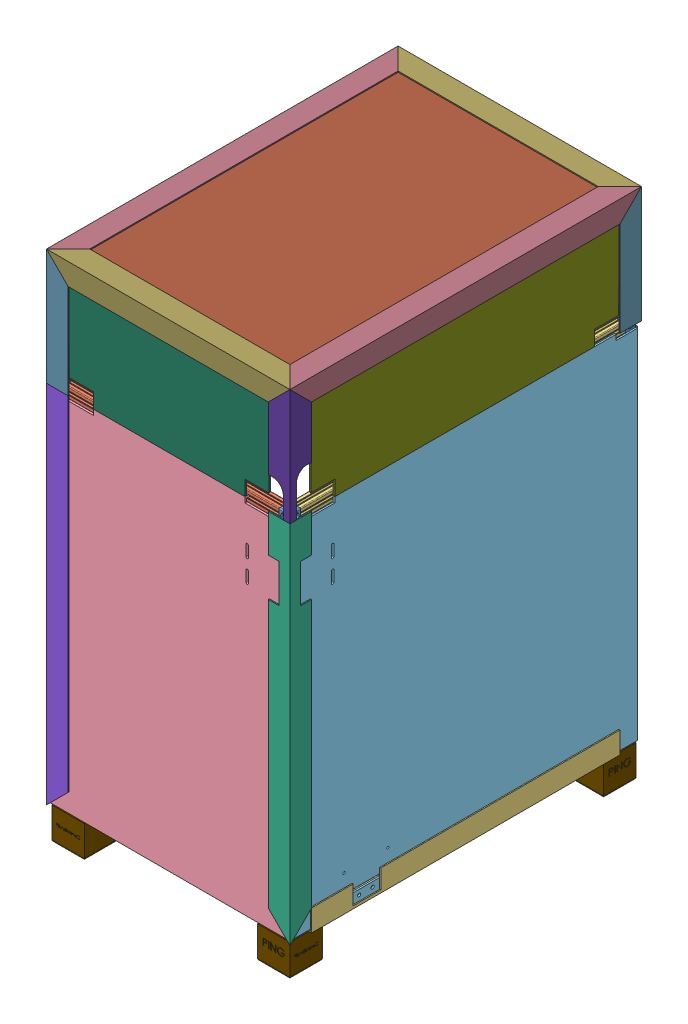
SolidWorks assembly carcasse, configuration Défaut. Lengths in mm.
Overall size (450 950 650).
53 component instances, 24 part files, 63 mates.
Components (placement in the parent):
- cadre-1: cadre [Défaut] at (-215.194 -19.8636 -400) size (440 20 640)
  - Blocks-1: Blocks [Défaut] at (-153.6103 82.5412 1245.1575) x (0 1 0) z (0 0 1) size (20 20 20)
  - Blocks-3: Blocks [Défaut] at (-153.6103 62.5412 625.1575) x (0 0 -1) z (0 1 0) size (20 20 20)
  - Blocks-4: Blocks [Défaut] at (246.3897 82.5412 645.1575) x (0 1 0) z (0 0 -1) size (20 20 20)
  - Blocks-5: Blocks [Défaut] at (246.3897 62.5412 1265.1575) x (0 0 1) z (0 1 0) size (20 20 20)
  - prof_20x20x400mm-1: prof_20x20x400mm [End Finishing_Non-Machined End Finish Options_Type_Single_] at (246.3897 72.5412 635.1575) x (0 0 1) z (-1 0 0) size (20 20 400)
  - prof_20x20x400mm-2: prof_20x20x400mm [End Finishing_Non-Machined End Finish Options_Type_Single_] at (246.3897 72.5412 1255.1575) x (0 0 1) z (-1 0 0) size (20 20 400)
  - prof_20x20x600mm-4: prof_20x20x600mm [End Finishing_Non-Machined End Finish Options_Type_Single_] at (256.3897 72.5412 645.1575) size (20 20 600)
  - prof_20x20x600mm-5: prof_20x20x600mm [End Finishing_Non-Machined End Finish Options_Type_Single_] at (-163.6103 72.5412 645.1575) size (20 20 600)
- prof_20x20x640mm-1: prof_20x20x640mm [End Finishing_Non-Machined End Finish Options_Type_Single_] at (41.1957 42.6776 235.1575) x (1 0 0) z (0 -1 0) size (20 20 640)
- prof_20x20x640mm-2: prof_20x20x640mm [End Finishing_Non-Machined End Finish Options_Type_Single_] at (41.1957 42.6776 855.1575) x (1 0 0) z (0 -1 0) size (20 20 640)
- prof_20x20x640mm-3: prof_20x20x640mm [End Finishing_Non-Machined End Finish Options_Type_Single_] at (-378.8043 42.6776 855.1575) x (1 0 0) z (0 -1 0) size (20 20 640)
- prof_20x20x640mm-4: prof_20x20x640mm [End Finishing_Non-Machined End Finish Options_Type_Single_] at (-378.8043 42.6776 235.1575) x (1 0 0) z (0 -1 0) size (20 20 640)
- cadre-2: cadre [Défaut] at (-122.4146 -534.7812 -400) x (-1 0 0) z (0 0 1) size (440 20 640)
  - Blocks-1: Blocks [Défaut] at (-153.6103 82.5412 1245.1575) x (0 1 0) z (0 0 1) size (20 20 20)
  - Blocks-3: Blocks [Défaut] at (-153.6103 62.5412 625.1575) x (0 0 -1) z (0 1 0) size (20 20 20)
  - Blocks-4: Blocks [Défaut] at (246.3897 82.5412 645.1575) x (0 1 0) z (0 0 -1) size (20 20 20)
  - Blocks-5: Blocks [Défaut] at (246.3897 62.5412 1265.1575) x (0 0 1) z (0 1 0) size (20 20 20)
  - prof_20x20x400mm-1: prof_20x20x400mm [End Finishing_Non-Machined End Finish Options_Type_Single_] at (246.3897 72.5412 635.1575) x (0 0 1) z (-1 0 0) size (20 20 400)
  - prof_20x20x400mm-2: prof_20x20x400mm [End Finishing_Non-Machined End Finish Options_Type_Single_] at (246.3897 72.5412 1255.1575) x (0 0 1) z (-1 0 0) size (20 20 400)
  - prof_20x20x600mm-4: prof_20x20x600mm [End Finishing_Non-Machined End Finish Options_Type_Single_] at (256.3897 72.5412 645.1575) size (20 20 600)
  - prof_20x20x600mm-5: prof_20x20x600mm [End Finishing_Non-Machined End Finish Options_Type_Single_] at (-163.6103 72.5412 645.1575) size (20 20 600)
- plaque_acrylique_680x670-2: plaque_acrylique_680x670 [Défaut] at (51.1957 -282.3224 525.1575) x (0 0 -1) z (1 0 0) size (640 670 3)
- plaque_acrylique_380x670_G-1: plaque_acrylique_380x670_G [Défaut] at (-138.8043 -282.3224 222.1575) size (440 670 3)
- plaque_acrylique_680x670_porte-1: plaque_acrylique_680x670_porte [Défaut] at (-391.8043 -282.3224 525.1575) x (0 0 -1) z (1 0 0) size (640 670 3)
- eclisse_40x40x670_bisote_x1-1: eclisse_40x40x670_bisote_x1 [Défaut] at (-373.8043 -622.3224 240.2711) size (40 675 40)
- eclisse_40x40x670_bisote_x1-2: eclisse_40x40x670_bisote_x1 [Défaut] at (-373.6907 -622.3224 850.1575) x (0 0 -1) z (1 0 0) size (40 675 40)
- eclisse_40x40x670_bisote_x1-4: eclisse_40x40x670_bisote_x1 [Défaut] at (36.0821 -622.3224 240.1575) x (0 0 1) z (-1 0 0) size (40 675 40) (hidden)
- couvercle-1: couvercle [Défaut] at (191.3923 156.5575 835.9918) size (450 215 650)
  - plaque_acrylique_680x210-2: plaque_acrylique_680x210 [Défaut] at (-583.1966 1.1201 -270.8343) x (0 0 -1) z (1 0 0) size (640 210 3)
  - plaque_acrylique_380x210-2: plaque_acrylique_380x210 [Défaut] at (-330.1966 1.1201 -613.8343) size (440 210 3)
  - plaque_acrylique_380x680-1: plaque_acrylique_380x680 [Défaut] at (-330.1966 106.1201 -270.8343) x (1 0 0) z (0 1 0) size (440 640 3)
  - eclisse_40x40x404_bisote_x2-1: eclisse_40x40x404_bisote_x2 [Défaut] at (-135.1966 91.0065 -595.8343) x (0 0 1) z (0 -1 0) size (40 450 40)
  - eclisse_40x40x704_bisote_x2-1: eclisse_40x40x704_bisote_x2 [Défaut] at (-155.3102 91.1201 -615.8343) x (0 -1 0) z (-1 0 0) size (40 650 40)
  - eclisse_40x40x404_bisote_x2-2: eclisse_40x40x404_bisote_x2 [Défaut] at (-585.1966 91.0065 14.1657) x (0 0 -1) z (0 -1 0) size (40 450 40)
  - eclisse_40x40x704_bisote_x2-2: eclisse_40x40x704_bisote_x2 [Défaut] at (-565.1966 91.0065 -615.8343) x (1 0 0) z (0 -1 0) size (40 650 40)
  - eclisse_40x40x222_bisote_x1-1: eclisse_40x40x222_bisote_x1 [Défaut] at (-565.083 111.1201 -595.8343) x (0 0 1) z (1 0 0) size (40 215 40)
  - eclisse_40x40x222_bisote_x1-2: eclisse_40x40x222_bisote_x1 [Défaut] at (-155.1966 111.1201 -595.7207) x (-1 0 0) z (0 0 1) size (40 215 40)
  - eclisse_40x40x222_bisote_x1-4: eclisse_40x40x222_bisote_x1 [Défaut] at (-565.1966 111.1201 14.052) x (1 0 0) z (0 0 -1) size (40 215 40)
  - plaque_acrylique_380x210_Moteur-1: plaque_acrylique_380x210_Moteur [Défaut] at (-330.1966 1.1201 29.1657) size (440 210 3)
  - plaque_acrylique_680x210_moteur-1: plaque_acrylique_680x210_moteur [Défaut] at (-140.1966 1.1201 -270.8343) x (0 0 -1) z (1 0 0) size (640 210 3)
  - eclisse_40x40x222_bisote_x1_Moteur-1: eclisse_40x40x222_bisote_x1_Moteur [Défaut] at (-155.3102 111.1201 14.1657) x (0 0 -1) z (-1 0 0) size (40 215 40)
- Pied-1: Pied [Défaut] at (-8.8043 -622.3224 285.1575) x (-1 0 0) z (0 -1 0) size (60 60 60)
- Pied-2: Pied [Défaut] at (-8.8043 -622.3224 805.1575) x (0 0 -1) z (0 -1 0) size (60 60 60)
- Pied-3: Pied [Défaut] at (-328.8043 -622.3224 805.1575) x (1 0 0) z (0 -1 0) size (60 60 60)
- Pied-4: Pied [Défaut] at (-328.8043 -622.3224 285.1575) x (0 0 1) z (0 -1 0) size (60 60 60)
- eclisse_bas_40x40x704-2: eclisse_bas_40x40x704 [Défaut] at (-373.8043 -602.2087 830.1575) x (1 0 0) z (0 1 0) size (40 570 40) (hidden)
- eclisse_bas_40x40x404-1: eclisse_bas_40x40x404 [Défaut] at (-353.8043 -602.2087 240.1575) x (0 0 1) z (0 1 0) size (40 370 40) (hidden)
- eclisse_bas_40x40x404-2: eclisse_bas_40x40x404 [Défaut] at (16.1957 -602.2087 850.1575) x (0 0 -1) z (0 1 0) size (40 370 40) (hidden)
- eclisse_bas_support_Z_40x40x704-1: eclisse_bas_support_Z_40x40x704 [Défaut] at (36.0821 -602.3224 830.1575) x (0 1 0) z (-1 0 0) size (40 570 40) (hidden)
- plaque_acrylique_380x670_D-2: plaque_acrylique_380x670_D [Défaut] at (-198.8043 -282.3224 848.1575) x (-1 0 0) z (0 0 -1) size (440 670 23) (hidden)
- plaque_acrylique_bas_380x680-1: plaque_acrylique_bas_380x680 [Défaut] at (-138.8043 -620.3224 565.1575) x (1 0 0) z (0 1 0) size (440 640 3)
- eclisse_40x40x670_bisote_x1-Moteur-1: eclisse_40x40x670_bisote_x1-Moteur [Défaut] at (36.1957 -622.3224 850.0438) x (-1 0 0) z (0 0 -1) size (40 675 40) (hidden)
Mates (geometry in assembly coordinates):
- Coïncidente66: coincident anti-aligned: plane of plaque_acrylique_680x670_porte-1 through (-391.8043 -282.3224 525.1575) normal (-1 0 0); plane of eclisse_40x40x670_bisote_x1-1 through (-391.8043 52.6776 222.1575) normal (1 0 0)
- Coïncidente67: coincident aligned: plane of plaque_acrylique_680x670_porte-1 through (-388.8043 52.6776 865.1575) normal (0 1 0); plane of eclisse_40x40x670_bisote_x1-1 through (-373.8043 52.6776 240.2711) normal (0 1 0)
- Coïncidente68: coincident anti-aligned: plane of plaque_acrylique_680x670-2 through (54.1957 -282.3224 525.1575) normal (1 0 0); plane of eclisse_40x40x670_bisote_x1-4 through (54.1957 52.6776 222.1575) normal (-1 0 0)
- Coïncidente72: coincident anti-aligned: plane of plaque_acrylique_680x670_porte-1 through (-391.8043 -282.3224 525.1575) normal (-1 0 0); plane of eclisse_40x40x670_bisote_x1-2 through (-391.8043 52.6776 868.1575) normal (1 0 0)
- Coïncidente100: coincident: plane of plaque_acrylique_680x670_porte-1 through (-388.8043 52.6776 865.1575) normal (0 1 0); line of eclisse_40x40x670_bisote_x1-2 through (-391.8043 52.6776 868.1575) axis (0 0 -1)
- Coïncidente132: coincident anti-aligned: plane of plaque_acrylique_680x670_porte-1 through (-391.8043 -282.3224 525.1575) normal (-1 0 0); plane of eclisse_bas_40x40x704-2 through (-391.8043 -620.3224 260.1575) normal (1 0 0)
- Coïncidente134: coincident anti-aligned: line of eclisse_40x40x670_bisote_x1-2 through (-393.8043 52.6776 830.1575) axis (0 -1 0); line of eclisse_bas_40x40x704-2 through (-393.8043 -622.3224 830.1575) axis (0 1 0)
- Coïncidente142: coincident anti-aligned: plane of plaque_acrylique_680x670-2 through (54.1957 -282.3224 525.1575) normal (1 0 0); plane of eclisse_bas_support_Z_40x40x704-1 through (54.1957 -620.3224 260.1575) normal (-1 0 0)
- Coïncidente156: coincident anti-aligned: plane of eclisse_bas_40x40x404-2 through (-353.8043 -620.3224 868.1575) normal (0 0 -1); plane of plaque_acrylique_380x670_D-2 through (-198.8043 -282.3224 868.1575) normal (0 0 1)
- Coïncidente157: coincident anti-aligned: plane of eclisse_40x40x670_bisote_x1-2 through (-391.8043 52.6776 868.1575) normal (0 0 -1); plane of plaque_acrylique_380x670_D-2 through (-198.8043 -282.3224 868.1575) normal (0 0 1)
- Coïncidente163: coincident anti-aligned: plane of cadre-1/Blocks-1 through (-388.8043 42.6776 865.1575) normal (0 -1 0); plane of prof_20x20x640mm-3 through (-387.3043 42.6776 863.6575) normal (0 1 0)
- Coïncidente164: coincident aligned: plane of cadre-1/Blocks-1 through (-388.8043 42.6776 865.1575) normal (-1 0 0); plane of prof_20x20x640mm-3 through (-388.8043 -597.3224 858.9075) normal (-1 0 0)
- Coïncidente165: coincident aligned: plane of cadre-1/Blocks-1 through (-368.8043 62.6776 865.1575) normal (0 0 1); plane of prof_20x20x640mm-3 through (-382.5543 -597.3224 865.1575) normal (0 0 1)
- Coïncidente166: coincident anti-aligned: plane of prof_20x20x640mm-3 through (-387.3043 -597.3224 863.6575) normal (0 -1 0); plane of cadre-2/Blocks-5 through (-368.8043 -597.3224 865.1575) normal (0 1 0)
- Coïncidente167: coincident aligned: plane of prof_20x20x640mm-3 through (-382.5543 -597.3224 865.1575) normal (0 0 1); plane of cadre-2/Blocks-5 through (-388.8043 -617.3224 865.1575) normal (0 0 1)
- Coïncidente168: coincident aligned: plane of prof_20x20x640mm-3 through (-388.8043 -597.3224 858.9075) normal (-1 0 0); plane of cadre-2/Blocks-5 through (-388.8043 -617.3224 845.1575) normal (-1 0 0)
- Coïncidente169: coincident anti-aligned: plane of prof_20x20x640mm-2 through (32.6957 -597.3224 863.6575) normal (0 -1 0); plane of cadre-2/Blocks-1 through (51.1957 -597.3224 865.1575) normal (0 1 0)
- Coïncidente170: coincident aligned: plane of prof_20x20x640mm-2 through (37.4457 -597.3224 865.1575) normal (0 0 1); plane of cadre-2/Blocks-1 through (31.1957 -617.3224 865.1575) normal (0 0 1)
- Coïncidente171: coincident aligned: plane of prof_20x20x640mm-2 through (51.1957 -597.3224 858.9075) normal (1 0 0); plane of cadre-2/Blocks-1 through (51.1957 -597.3224 865.1575) normal (1 0 0)
- Coïncidente172: coincident anti-aligned: plane of prof_20x20x640mm-1 through (32.6957 -597.3224 243.6575) normal (0 -1 0); plane of cadre-2/Blocks-3 through (31.1957 -597.3224 225.1575) normal (0 1 0)
- Coïncidente173: coincident aligned: plane of prof_20x20x640mm-1 through (51.1957 -597.3224 238.9075) normal (1 0 0); plane of cadre-2/Blocks-3 through (51.1957 -617.3224 245.1575) normal (1 0 0)
- Coïncidente174: coincident aligned: plane of prof_20x20x640mm-1 through (44.9457 -597.3224 225.1575) normal (0 0 -1); plane of cadre-2/Blocks-3 through (51.1957 -617.3224 225.1575) normal (0 0 -1)
- Coïncidente175: coincident aligned: plane of cadre-1/Blocks-3 through (-388.8043 62.6776 245.1575) normal (-1 0 0); plane of prof_20x20x640mm-4 through (-388.8043 -597.3224 231.4075) normal (-1 0 0)
- Coïncidente176: coincident aligned: plane of cadre-1/Blocks-3 through (-388.8043 62.6776 225.1575) normal (0 0 -1); plane of prof_20x20x640mm-4 through (-382.5543 -597.3224 225.1575) normal (0 0 -1)
- Coïncidente177: coincident anti-aligned: plane of cadre-1/Blocks-3 through (-368.8043 42.6776 225.1575) normal (0 -1 0); plane of prof_20x20x640mm-4 through (-387.3043 42.6776 243.6575) normal (0 1 0)
- Coïncidente183: coincident aligned: plane of prof_20x20x640mm-2 through (51.1957 -597.3224 858.9075) normal (1 0 0); plane of plaque_acrylique_380x670_D-2 through (51.1957 52.6776 868.1575) normal (1 0 0)
- Coïncidente186: coincident aligned: plane of cadre-1/prof_20x20x400mm-2 through (-368.8043 56.4276 865.1575) normal (0 0 1); plane of plaque_acrylique_680x670-2 through (54.1957 52.6776 865.1575) normal (0 0 1)
- Coïncidente187: coincident aligned: plane of cadre-1/prof_20x20x400mm-1 through (-368.8043 48.9276 225.1575) normal (0 0 -1); plane of plaque_acrylique_680x670_porte-1 through (-388.8043 52.6776 225.1575) normal (0 0 -1)
- Coïncidente191: coincident anti-aligned: plane of cadre-2/prof_20x20x400mm-1 through (31.1957 -617.3224 238.9075) normal (0 -1 0); plane of plaque_acrylique_bas_380x680-1 through (-138.8043 -617.3224 565.1575) normal (0 1 0)
- Coïncidente192: coincident aligned: plane of cadre-2/prof_20x20x400mm-2 through (31.1957 -611.0724 865.1575) normal (0 0 1); plane of plaque_acrylique_bas_380x680-1 through (-388.8043 -617.3224 865.1575) normal (0 0 1)
- Coïncidente204: coincident anti-aligned: plane of prof_20x20x640mm-1 through (44.9457 -597.3224 225.1575) normal (0 0 -1); plane of plaque_acrylique_380x670_G-1 through (-138.8043 -282.3224 225.1575) normal (0 0 1)
- Coïncidente205: coincident aligned: plane of cadre-2/prof_20x20x400mm-1 through (31.1957 -617.3224 231.4075) normal (0 -1 0); plane of plaque_acrylique_380x670_G-1 through (-388.8043 -617.3224 225.1575) normal (0 -1 0)
- Coïncidente206: coincident aligned: plane of prof_20x20x640mm-1 through (51.1957 -597.3224 231.4075) normal (1 0 0); plane of plaque_acrylique_380x670_G-1 through (51.1957 52.6776 225.1575) normal (1 0 0)
- Coïncidente207: coincident anti-aligned: plane of prof_20x20x640mm-4 through (-388.8043 -597.3224 231.4075) normal (-1 0 0); plane of plaque_acrylique_680x670_porte-1 through (-388.8043 -282.3224 525.1575) normal (1 0 0)
- Coïncidente208: coincident anti-aligned: plane of plaque_acrylique_380x670_G-1 through (-138.8043 -282.3224 222.1575) normal (0 0 -1); plane of eclisse_40x40x670_bisote_x1-1 through (-391.8043 52.6776 222.1575) normal (0 0 1)
- Coïncidente210: coincident anti-aligned: plane of plaque_acrylique_380x670_G-1 through (-138.8043 -282.3224 222.1575) normal (0 0 -1); plane of eclisse_40x40x670_bisote_x1-4 through (54.1957 52.6776 222.1575) normal (0 0 1)
- Coïncidente218: coincident: plane of cadre-2/prof_20x20x400mm-2 through (31.1957 -617.3224 858.9075) normal (0 -1 0); line of plaque_acrylique_380x670_D-2 through (51.1957 -617.3224 868.1575) axis (-1 0 0)
- Coïncidente223: coincident anti-aligned: plane of eclisse_bas_support_Z_40x40x704-1 through (54.1957 -620.3224 260.1575) normal (0 1 0); plane of plaque_acrylique_bas_380x680-1 through (-138.8043 -620.3224 565.1575) normal (0 -1 0)
- Coïncidente224: coincident anti-aligned: plane of eclisse_bas_40x40x704-2 through (-391.8043 -620.3224 260.1575) normal (0 1 0); plane of plaque_acrylique_bas_380x680-1 through (-138.8043 -620.3224 565.1575) normal (0 -1 0)
- Coïncidente225: coincident anti-aligned: plane of plaque_acrylique_380x670_G-1 through (-138.8043 -282.3224 222.1575) normal (0 0 -1); plane of eclisse_bas_40x40x404-1 through (16.1957 -620.3224 222.1575) normal (0 0 1)
- Coïncidente226: coincident anti-aligned: plane of eclisse_bas_40x40x404-1 through (16.1957 -620.3224 222.1575) normal (0 1 0); plane of plaque_acrylique_bas_380x680-1 through (-138.8043 -620.3224 565.1575) normal (0 -1 0)
- Coïncidente232: coincident aligned: plane of plaque_acrylique_380x670_G-1 through (-138.8043 -282.3224 222.1575) normal (0 0 -1); plane of couvercle-1/plaque_acrylique_380x210-2 through (-138.8043 157.6776 222.1575) normal (0 0 -1)
- Coïncidente233: coincident aligned: plane of couvercle-1/plaque_acrylique_380x210_Moteur-1 through (-138.8043 157.6776 868.1575) normal (0 0 1); plane of plaque_acrylique_380x670_D-2 through (-198.8043 -282.3224 868.1575) normal (0 0 1)
- Coïncidente234: coincident anti-aligned: line of plaque_acrylique_680x670-2 through (54.1957 52.6776 265.1575) axis (0 0 1); line of couvercle-1/plaque_acrylique_680x210_moteur-1 through (54.1957 52.6776 785.1575) axis (0 0 -1)
- Coïncidente235: coincident aligned: plane of plaque_acrylique_680x670-2 through (54.1957 -282.3224 525.1575) normal (1 0 0); plane of couvercle-1/plaque_acrylique_680x210_moteur-1 through (54.1957 157.6776 565.1575) normal (1 0 0)
- Coïncidente236: coincident anti-aligned: plane of plaque_acrylique_680x670-2 through (54.1957 -282.3224 525.1575) normal (1 0 0); plane of eclisse_40x40x670_bisote_x1-Moteur-1 through (54.1957 52.6776 868.1575) normal (-1 0 0)
- Coïncidente237: coincident anti-aligned: plane of plaque_acrylique_380x670_D-2 through (-198.8043 -282.3224 868.1575) normal (0 0 1); plane of eclisse_40x40x670_bisote_x1-Moteur-1 through (54.1957 52.6776 868.1575) normal (0 0 -1)
- Coïncidente239: coincident anti-aligned: plane of plaque_acrylique_680x670_porte-1 through (-388.8043 -282.3224 525.1575) normal (1 0 0); plane of plaque_acrylique_bas_380x680-1 through (-388.8043 -617.3224 225.1575) normal (-1 0 0)
- Coïncidente240: coincident anti-aligned: plane of cadre-2/prof_20x20x600mm-5 through (51.1957 -611.0724 845.1575) normal (1 0 0); plane of plaque_acrylique_680x670-2 through (51.1957 -282.3224 525.1575) normal (-1 0 0)
- Coïncidente241: coincident aligned: plane of cadre-2/prof_20x20x600mm-5 through (44.9457 -617.3224 845.1575) normal (0 -1 0); plane of plaque_acrylique_680x670-2 through (54.1957 -617.3224 865.1575) normal (0 -1 0)
- Coïncidente242: coincident aligned: plane of cadre-2/prof_20x20x600mm-4 through (-382.5543 -617.3224 845.1575) normal (0 -1 0); plane of plaque_acrylique_680x670_porte-1 through (-388.8043 -617.3224 865.1575) normal (0 -1 0)
- Coïncidente243: coincident anti-aligned: plane of eclisse_bas_40x40x404-2 through (-353.8043 -620.3224 868.1575) normal (0 1 0); plane of plaque_acrylique_bas_380x680-1 through (-138.8043 -620.3224 565.1575) normal (0 -1 0)
- Coïncidente244: coincident anti-aligned: plane of Pied-2 through (-8.8043 -622.3224 805.1575) normal (0 1 0); plane of eclisse_bas_40x40x404-2 through (-353.8043 -622.3224 870.1575) normal (0 -1 0)
- Coïncidente245: coincident anti-aligned: plane of Pied-4 through (-328.8043 -622.3224 285.1575) normal (0 1 0); plane of eclisse_bas_40x40x704-2 through (-393.8043 -622.3224 260.1575) normal (0 -1 0)
- Coïncidente246: coincident anti-aligned: plane of Pied-1 through (-8.8043 -622.3224 285.1575) normal (0 1 0); plane of eclisse_bas_40x40x404-1 through (16.1957 -622.3224 220.1575) normal (0 -1 0)
- Coïncidente247: coincident aligned: plane of cadre-2/prof_20x20x600mm-4 through (-388.8043 -603.5724 845.1575) normal (-1 0 0); plane of Pied-3 through (-388.8043 -682.3224 805.1575) normal (-1 0 0)
- Coïncidente249: coincident aligned: plane of cadre-2/prof_20x20x400mm-2 through (31.1957 -611.0724 865.1575) normal (0 0 1); plane of Pied-3 through (-328.8043 -682.3224 865.1575) normal (0 0 1)
- Coïncidente250: coincident aligned: plane of cadre-2/prof_20x20x600mm-5 through (51.1957 -603.5724 845.1575) normal (1 0 0); plane of Pied-2 through (51.1957 -682.3224 805.1575) normal (1 0 0)
- Coïncidente251: coincident aligned: plane of cadre-2/prof_20x20x400mm-2 through (31.1957 -603.5724 865.1575) normal (0 0 1); plane of Pied-2 through (-8.8043 -682.3224 865.1575) normal (0 0 1)
- Coïncidente252: coincident aligned: plane of cadre-2/prof_20x20x600mm-5 through (51.1957 -611.0724 845.1575) normal (1 0 0); plane of Pied-1 through (51.1957 -682.3224 285.1575) normal (1 0 0)
- Coïncidente253: coincident aligned: plane of cadre-2/prof_20x20x400mm-1 through (31.1957 -611.0724 225.1575) normal (0 0 -1); plane of Pied-1 through (-8.8043 -682.3224 225.1575) normal (0 0 -1)
- Coïncidente254: coincident aligned: plane of cadre-2/prof_20x20x600mm-4 through (-388.8043 -611.0724 845.1575) normal (-1 0 0); plane of Pied-4 through (-388.8043 -682.3224 285.1575) normal (-1 0 0)
- Coïncidente255: coincident aligned: plane of cadre-2/prof_20x20x400mm-1 through (31.1957 -611.0724 225.1575) normal (0 0 -1); plane of Pied-4 through (-328.8043 -682.3224 225.1575) normal (0 0 -1)
